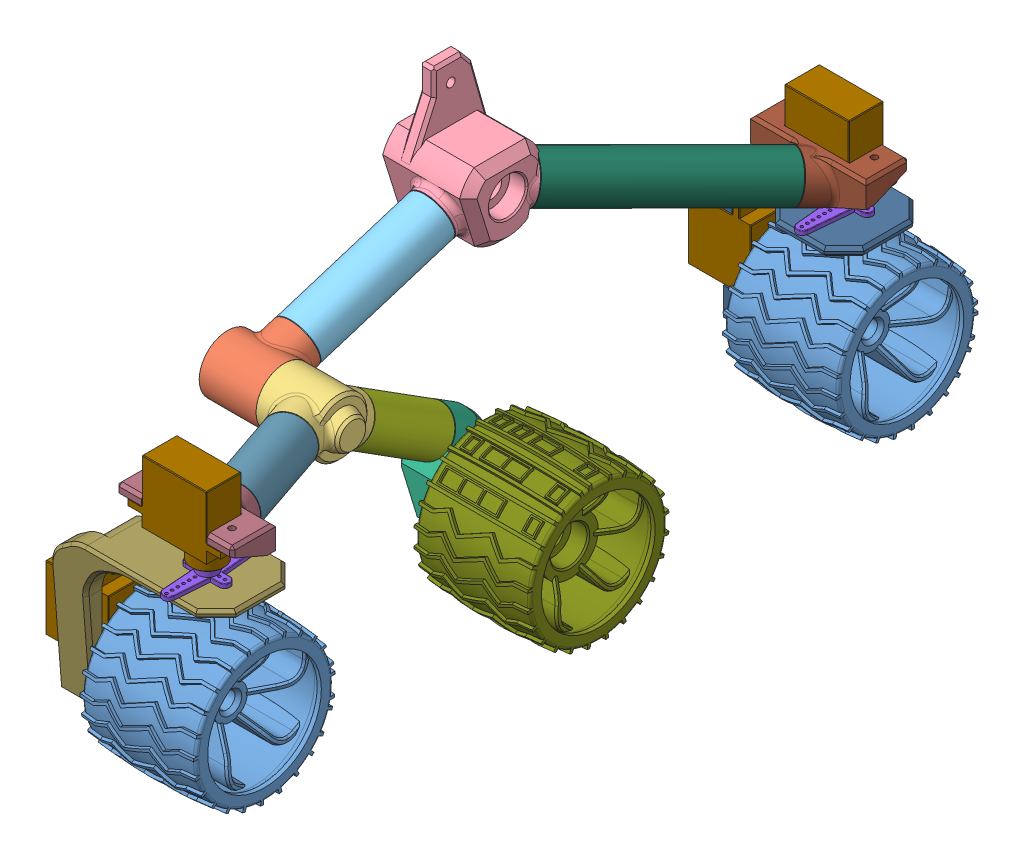
SolidWorks assembly suspensionSub-right, configuration Default. Lengths in mm.
Overall size (100.09 192.91 286.94).
24 component instances, 17 part files, 62 mates.
Components (placement in the parent):
- suspension3D-report-1: suspension3D-report [Default] at (24.2234 -21.993 143.476) size (100 158.78 276)
- tire-1: tire [Default] at (4.2234 -21.993 143.476) x (0 -0.999427 0.033856) z (1 0 0) size (53.45 55.85 40.12)
- tire-3: tire [Default] at (4.2234 -21.993 -82.524) x (0 -0.984808 0.173648) z (1 0 0) size (53.45 55.85 40.12)
- bogieJointFixed-right-1: bogieJointFixed-right [Default] at (-50.7766 18.817 81.456) x (0 0.297904 -0.954596) z (1 0 0) size (40 20 21.53)
- bogieJointFree-right-2: bogieJointFree-right [Default] at (-30.7766 18.817 81.456) x (1 0 0) z (0 0.534644 0.845077) size (27.04 27.37 57.25)
- rockerJoint-right-1: rockerJoint-right [Default] at (-58.2766 42.597 5.256) x (1 0 0) z (0 -0.297904 0.954596) size (35.64 50.55 55.79)
- aftRockerTube-1: aftRockerTube [Default] at (-40.7766 23.2868 67.1329) x (0.858574 -0.489411 -0.152732) z (0.512689 0.819591 0.255773) size (15.88 49.82 15.88)
- wheelStrut-mid-left-1: wheelStrut-mid-left [Default] at (-20.7766 -21.993 36.076) size (23.13 36.67 28.96)
- foreBogieTube-1: foreBogieTube [Default] at (-20.7766 -7.2198 40.3014) x (1 0 0) z (0 -0.845077 0.534644) size (15.88 33.7 15.88)
- sg90ServoHorn-star-1: sg90ServoHorn-star [Default] at (-15.7766 -23.893 -79.674) x (0 1 0) z (0 0 1) size (34.4 4 15.7)
- sg90Servo-1: sg90Servo [Default] at (-46.7446 -27.743 -88.674) x (0 1 0) z (0 0 -1) size (32.7 29.37 12.3)
- sg90ServoHorn-star-2: sg90ServoHorn-star [Default] at (-15.7766 -23.893 146.326) x (0 1 0) z (0 0 1) size (34.4 4 15.7)
- sg90Servo-2: sg90Servo [Default] at (-46.7446 -27.743 137.326) x (0 1 0) z (0 0 -1) size (32.7 29.37 12.3)
- wheelStrut-front-right-v2-1: wheelStrut-front-right-v2 [Default] at (-46.7446 -27.743 -88.674) x (0 1 0) z (0 0 -1) size (50.75 59.16 31.22)
- sg90ServoHorn-star-3: sg90ServoHorn-star [Default] at (7.0734 13.007 -80.624) x (0 0 -1) z (1 0 0) size (34.4 4 15.7)
- sg90Servo-3: sg90Servo [Default] at (9.9734 43.975 -76.374) x (-1 0 0) z (0 0 1) size (32.7 29.37 12.3)
- wheelPivot-front-right-v2-1: wheelPivot-front-right-v2 [Default] at (9.9734 43.975 -76.374) x (-1 0 0) z (0 0 1) size (40.7 16.47 34.17)
- wheelStrut-rear-right-v2-2: wheelStrut-rear-right-v2 [Default] at (-46.7446 -27.743 149.626) x (0 1 0) z (0 0 -1) size (50.75 59.16 31.22)
- sg90ServoHorn-star-4: sg90ServoHorn-star [Default] at (1.3734 13.007 141.576) x (0 0 1) z (-1 0 0) size (34.4 4 15.7)
- sg90Servo-4: sg90Servo [Default] at (9.9734 43.975 149.626) x (-1 0 0) z (0 0 1) size (32.7 29.37 12.3)
- wheelPivot-rear-right-v2-1: wheelPivot-rear-right-v2 [Default] at (9.9734 43.975 137.326) x (1 0 0) z (0 0 -1) size (40.7 18.75 35.49)
- aftBogieTube-1: aftBogieTube [Default] at (-15.1903 20.1331 95.3146) x (0.898204 -0.28457 -0.335037) z (-0.233519 -0.954631 0.184791) size (15.88 37.13 15.88)
- foreRockerTube-1: foreRockerTube [Default] at (-2.4655 24.4715 -69.4762) x (0.842254 0.427799 0.32802) z (0.302918 -0.878908 0.368458) size (15.88 70.91 15.88)
- tire-mid-1: tire-mid [Default] at (14.252 -21.993 36.076) x (0 0.377875 -0.925857) z (1 0 0) size (53.45 55.85 40.12)
Mates (geometry in assembly coordinates):
- Concentric1: concentric aligned: circle of tire-1; line of assembly
- Coincident1: coincident: point of suspension3D-report-1; plane of tire-1 through (-15.7766 -45.9768 144.2884) normal (-1 0 0)
- Concentric3: concentric aligned: circle of tire-3; line of assembly
- Coincident3: coincident: point of suspension3D-report-1; plane of tire-3 through (-15.7766 -45.626 -78.3569) normal (-1 0 0)
- Concentric4: concentric anti-aligned: circle of bogieJointFixed-right-1; line of assembly
- Concentric13: concentric aligned: line of suspension3D-report-1 through (-20.7766 18.817 81.456) axis (-1 0 0); cylinder of bogieJointFree-right-2 through (-10.7766 18.817 81.456) axis (-1 0 0) radius 10
- Concentric14: concentric aligned: line of suspension3D-report-1 through (4.2234 24.707 143.476) axis (-0.372423 -0.087743 -0.923906); cylinder of bogieJointFree-right-2 through (-15.1903 20.1331 95.3146) axis (-0.372423 -0.087743 -0.923906) radius 8
- Concentric15: concentric aligned: line of suspension3D-report-1 through (-40.7766 18.817 81.456) axis (0 0.297904 -0.954596); cylinder of rockerJoint-right-1 through (-40.7766 38.1284 19.5749) axis (0 0.297904 -0.954596) radius 8
- Concentric16: concentric anti-aligned: line of suspension3D-report-1 through (-40.7766 42.597 5.256) axis (0.445925 -0.210972 -0.869851); cylinder of rockerJoint-right-1 through (-34.0877 39.4324 -7.7918) axis (-0.445925 0.210972 0.869851) radius 8
- Concentric17: concentric anti-aligned: line of suspension3D-report-1 through (-40.7766 18.817 81.456) axis (0 0.297904 -0.954596); cylinder of bogieJointFixed-right-1 through (-40.7766 23.2855 67.137) axis (0 -0.297904 0.954596) radius 8
- Concentric18: concentric aligned: circle of rockerJoint-right-1; cylinder of aftRockerTube-1 through (-40.7766 38.1284 19.5749) axis (0 -0.297904 0.954596) radius 6.44
- Coincident20: coincident anti-aligned: plane of rockerJoint-right-1 through (-40.7766 38.1284 19.5749) normal (0 -0.297904 0.954596); plane of aftRockerTube-1 through (-40.7766 38.1284 19.5749) normal (0 0.297904 -0.954596)
- Concentric19: concentric aligned: line of suspension3D-report-1 through (-20.7766 18.817 81.456) axis (0 -0.534644 -0.845077); cylinder of wheelStrut-mid-left-1 through (-20.7766 -7.2198 40.3014) axis (0 -0.534644 -0.845077) radius 8
- Coincident27: coincident: line of suspension3D-report-1 through (-5.7766 -21.993 36.076) axis (-1 0 0); point of wheelStrut-mid-left-1
- Concentric20: concentric aligned: line of suspension3D-report-1 through (-20.7766 18.817 81.456) axis (0 -0.534644 -0.845077); cylinder of foreBogieTube-1 through (-20.7766 10.7977 68.7805) axis (0 -0.534644 -0.845077) radius 6.44
- Coincident29: coincident anti-aligned: plane of wheelStrut-mid-left-1 through (-20.7766 -7.2198 40.3014) normal (0 0.534644 0.845077); plane of foreBogieTube-1 through (-20.7766 -7.2198 40.3014) normal (0 -0.534644 -0.845077)
- Coincident54: coincident anti-aligned: plane of tire-3 through (-15.7766 -45.626 -78.3569) normal (-1 0 0); plane of sg90ServoHorn-star-1 through (-15.7766 -23.893 -79.674) normal (1 0 0)
- Concentric28: concentric aligned: line of suspension3D-report-1 through (24.2234 -21.993 -82.524) axis (-1 0 0); cylinder of sg90ServoHorn-star-1 through (-15.7756 -21.993 -82.524) axis (-1 0 0) radius 1.2
- Parallel14: parallel aligned: plane of sg90ServoHorn-star-1 through (-17.2366 -20.093 -79.674) normal (0 1 0); plane of assembly through (0 0 0) normal (0 1 0)
- Coincident57: coincident anti-aligned: plane of sg90ServoHorn-star-1 through (-17.3766 -21.993 -82.524) normal (-1 0 0); plane of sg90Servo-1 through (-17.3766 -21.993 -82.524) normal (1 0 0)
- Concentric29: concentric aligned: cylinder of sg90ServoHorn-star-1 through (-17.3766 -21.993 -82.524) axis (-1 0 0) radius 2.4; cylinder of sg90Servo-1 through (-17.3766 -21.993 -82.524) axis (-1 0 0) radius 1.984
- Parallel15: parallel anti-aligned: plane of sg90Servo-1 through (-24.5196 -27.743 -88.674) normal (0 0 -1); plane of assembly through (0 0 0) normal (0 0 1)
- Coincident59: coincident anti-aligned: plane of tire-1 through (-15.7766 -45.9768 144.2884) normal (-1 0 0); plane of sg90ServoHorn-star-2 through (-15.7766 -23.893 146.326) normal (1 0 0)
- Concentric33: concentric aligned: line of suspension3D-report-1 through (24.2234 -21.993 143.476) axis (-1 0 0); cylinder of sg90ServoHorn-star-2 through (-15.7756 -21.993 143.476) axis (-1 0 0) radius 1.2
- Parallel16: parallel aligned: plane of suspension3D-report-1 through (24.2234 -21.993 143.476) normal (0 1 0); plane of sg90ServoHorn-star-2 through (-17.2366 -20.093 146.326) normal (0 1 0)
- Coincident62: coincident anti-aligned: plane of sg90ServoHorn-star-2 through (-17.3766 -21.993 143.476) normal (-1 0 0); plane of sg90Servo-2 through (-17.3766 -21.993 143.476) normal (1 0 0)
- Concentric30: concentric aligned: cylinder of sg90ServoHorn-star-2 through (-17.3766 -21.993 143.476) axis (-1 0 0) radius 2.4; cylinder of sg90Servo-2 through (-17.3766 -21.993 143.476) axis (-1 0 0) radius 1.984
- Parallel17: parallel anti-aligned: plane of sg90Servo-2 through (-24.5196 -27.743 137.326) normal (0 0 -1); plane of assembly through (0 0 0) normal (0 0 1)
- InPlace1: in place: plane of ? through (-24.5196 -27.743 -88.674) normal (0 0 -1); plane of ? through (0 0 -88.674) normal (0 0 -1); moOrthogonalPlaneRef_w of ? through (-24.5196 -27.743 -88.674) normal (0 0 -1); unknown of ?; plane of ? through (-24.5196 -27.743 -88.674) normal (0 0 -1); plane of ? through (0 0 -88.674) normal (-1 0 0); plane of ? through (-24.5196 -27.743 -88.674) normal (0 0 -1); unknown of ?
- Coincident64: coincident aligned: plane of sg90Servo-1; plane of wheelStrut-front-right-v2-1
- Coincident65: coincident aligned: moOrthogonalPlaneRef_w of sg90Servo-1 through (-46.7446 -27.743 -88.674) normal (1 0 0); plane of wheelStrut-front-right-v2-1
- Coincident66: coincident anti-aligned: moOrthogonalPlaneRef_w of sg90Servo-1 through (-46.7446 -27.743 -88.674) normal (0 -1 0); plane of wheelStrut-front-right-v2-1
- Coincident67: coincident anti-aligned: plane of wheelStrut-front-right-v2-1 through (-46.7446 13.007 -95.674) normal (0 1 0); plane of sg90ServoHorn-star-3 through (7.0734 13.007 -80.624) normal (0 -1 0)
- Concentric31: concentric aligned: cylinder of wheelStrut-front-right-v2-1 through (4.2234 -37.7441 -82.524) axis (0 1 0) radius 2.4; cylinder of sg90ServoHorn-star-3 through (4.2234 13.006 -82.524) axis (0 1 0) radius 1.2
- Parallel18: parallel anti-aligned: plane of sg90ServoHorn-star-3 through (7.0734 14.467 -84.424) normal (0 0 -1); plane of wheelStrut-front-right-v2-1 through (-46.7446 -27.743 -64.374) normal (0 0 1)
- Coincident69: coincident anti-aligned: plane of sg90ServoHorn-star-3 through (4.2234 14.607 -82.524) normal (0 1 0); plane of sg90Servo-3 through (4.2234 14.607 -82.524) normal (0 -1 0)
- Concentric32: concentric aligned: cylinder of sg90ServoHorn-star-3 through (4.2234 14.607 -82.524) axis (0 1 0) radius 2.4; cylinder of sg90Servo-3 through (4.2234 14.607 -82.524) axis (0 1 0) radius 1.984
- Parallel19: parallel aligned: plane of wheelStrut-front-right-v2-1 through (-46.7446 -27.743 -64.374) normal (0 0 1); plane of sg90Servo-3 through (9.9734 21.75 -76.374) normal (0 0 1)
- InPlace2: in place: plane of ? through (9.9734 21.75 -76.374) normal (0 0 1); plane of ? through (0 0 -76.374) normal (0 0 1); plane of ? through (9.9734 21.75 -76.374) normal (0 0 1); plane of ? through (0 0 -76.374) normal (0 1 0); plane of ? through (9.9734 21.75 -76.374) normal (0 0 1); plane of ? through (0 0 -76.374) normal (1 0 0); plane of ? through (9.9734 21.75 -76.374) normal (0 0 1); unknown of ?
- Coincident70: coincident aligned: plane of sg90Servo-3; plane of wheelPivot-front-right-v2-1
- Coincident71: coincident aligned: moOrthogonalPlaneRef_w of sg90Servo-3 through (9.9734 43.975 -76.374) normal (0 -1 0); plane of wheelPivot-front-right-v2-1
- Coincident72: coincident anti-aligned: moOrthogonalPlaneRef_w of sg90Servo-3 through (9.9734 43.975 -76.374) normal (1 0 0); plane of wheelPivot-front-right-v2-1
- Coincident78: coincident anti-aligned: plane of sg90Servo-2 through (-24.5196 -27.743 149.626) normal (0 0 1); plane of wheelStrut-rear-right-v2-2 through (-46.7446 -27.743 149.626) normal (0 0 -1)
- Concentric34: concentric aligned: cylinder of wheelStrut-rear-right-v2-2 through (4.2234 -37.7441 143.476) axis (0 1 0) radius 2.4; cylinder of sg90ServoHorn-star-4 through (4.2234 13.006 143.476) axis (0 1 0) radius 1.2
- Coincident79: coincident anti-aligned: plane of wheelStrut-rear-right-v2-2 through (-46.7446 13.007 156.626) normal (0 1 0); plane of sg90ServoHorn-star-4 through (1.3734 13.007 141.576) normal (0 -1 0)
- Parallel22: parallel aligned: plane of wheelStrut-rear-right-v2-2 through (-46.7446 -27.743 125.326) normal (0 0 -1); plane of sg90ServoHorn-star-4 through (1.3734 14.467 141.576) normal (0 0 -1)
- Coincident81: coincident anti-aligned: plane of sg90ServoHorn-star-4 through (4.2234 14.607 143.476) normal (0 1 0); plane of sg90Servo-4 through (4.2234 14.607 143.476) normal (0 -1 0)
- Concentric35: concentric aligned: cylinder of sg90ServoHorn-star-4 through (4.2234 14.607 143.476) axis (0 1 0) radius 2.4; cylinder of sg90Servo-4 through (4.2234 14.607 143.476) axis (0 1 0) radius 1.984
- Coincident82: coincident aligned: plane of wheelStrut-rear-right-v2-2 through (-24.5196 -27.743 137.326) normal (0 0 -1); plane of sg90Servo-4 through (9.9734 21.75 137.326) normal (0 0 -1)
- InPlace3: in place: plane of sg90Servo-4 through (9.9734 21.75 137.326) normal (0 0 -1); plane of ? through (0 0 137.326) normal (0 0 -1); plane of sg90Servo-4 through (9.9734 21.75 137.326) normal (0 0 -1); unknown of ?; plane of sg90Servo-4 through (9.9734 21.75 137.326) normal (0 0 -1); plane of ? through (0 0 137.326) normal (-1 0 0); plane of sg90Servo-4 through (9.9734 21.75 137.326) normal (0 0 -1); unknown of wheelPivot-rear-right-v2-1
- Coincident83: coincident aligned: plane of sg90Servo-4; plane of wheelPivot-rear-right-v2-1
- Coincident84: coincident aligned: moOrthogonalPlaneRef_w of sg90Servo-4 through (9.9734 43.975 137.326) normal (0 -1 0); plane of wheelPivot-rear-right-v2-1 through (9.9734 43.975 137.326) normal (0 -1 0)
- Coincident85: coincident anti-aligned: moOrthogonalPlaneRef_w of sg90Servo-4 through (9.9734 43.975 137.326) normal (-1 0 0); plane of wheelPivot-rear-right-v2-1
- Concentric36: concentric aligned: cylinder of bogieJointFree-right-2 through (-15.1903 20.1331 95.3146) axis (-0.372423 -0.087743 -0.923906) radius 8; cylinder of aftBogieTube-1 through (-1.3622 23.391 129.6192) axis (-0.372423 -0.087743 -0.923906) radius 6.44
- Coincident86: coincident anti-aligned: plane of bogieJointFree-right-2 through (-15.1903 20.1331 95.3146) normal (0.372423 0.087743 0.923906); plane of aftBogieTube-1 through (-15.1903 20.1331 95.3146) normal (-0.372423 -0.087743 -0.923906)
- Concentric37: concentric aligned: cylinder of wheelPivot-front-right-v2-1 through (-2.4655 24.4715 -69.4762) axis (0.445925 -0.210972 -0.869851) radius 7.94; cylinder of foreRockerTube-1 through (-34.086 39.4316 -7.7951) axis (0.445925 -0.210972 -0.869851) radius 7.94
- Coincident87: coincident anti-aligned: plane of wheelPivot-front-right-v2-1 through (-2.4655 24.4715 -69.4762) normal (-0.445925 0.210972 0.869851); plane of foreRockerTube-1 through (-2.4655 24.4715 -69.4762) normal (0.445925 -0.210972 -0.869851)
- Coincident88: coincident aligned: line of sg90Servo-2 through (-31.1196 -4.793 137.576) axis (0 0 1); line of wheelStrut-rear-right-v2-2 through (-31.1196 -4.793 137.326) axis (0 0 1)
- Coincident89: coincident anti-aligned: line of sg90Servo-2 through (-31.1196 -27.993 149.376) axis (0 0 -1); line of wheelStrut-rear-right-v2-2 through (-31.1196 -27.993 137.326) axis (0 0 1)
- Concentric38: concentric aligned: line of suspension3D-report-1 through (34.2234 -21.993 36.076) axis (-1 0 0); cylinder of tire-mid-1 through (0.252 -21.993 36.076) axis (-1 0 0) radius 6.5
- Coincident93: coincident anti-aligned: plane of wheelStrut-mid-left-1 through (-5.748 -21.993 46.076) normal (1 0 0); plane of tire-mid-1 through (-5.748 -12.925 13.8577) normal (-1 0 0)
- Parallel23: parallel aligned: plane of tire-3 through (19.2234 -22.0349 -88.4329) normal (0 1 0); plane of sg90ServoHorn-star-1 through (-17.2366 -20.093 -79.674) normal (0 1 0)
